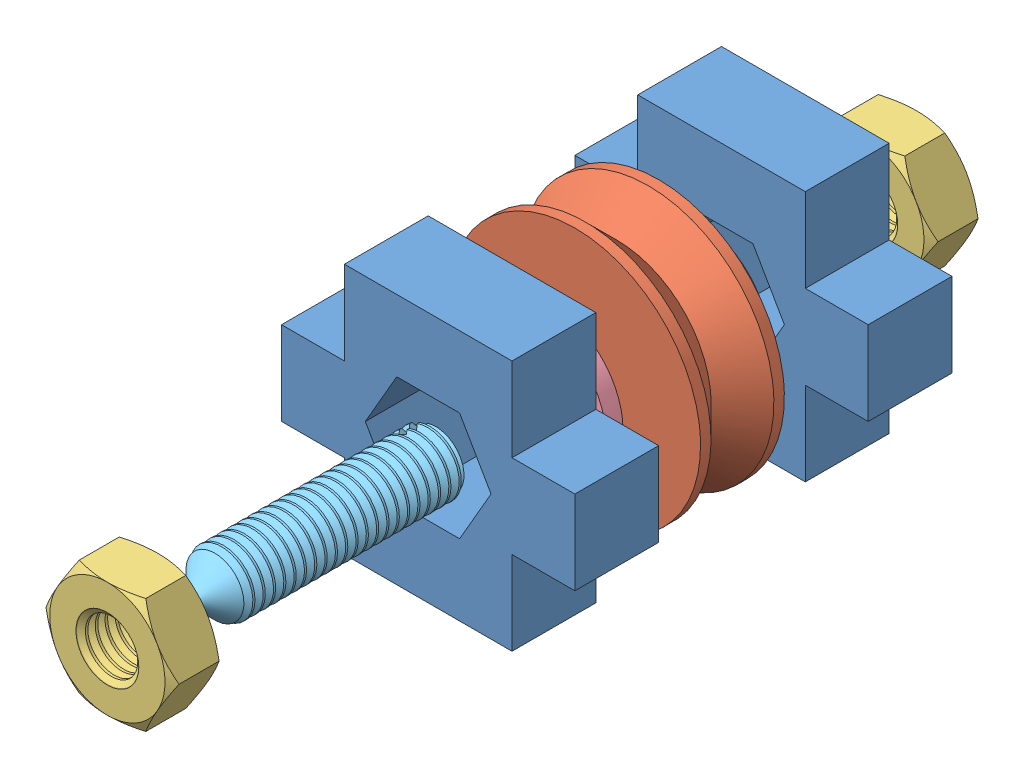
SolidWorks assembly pulleyInsidePalm, configuration Default. Lengths in mm.
Overall size (14 13.03 38.8).
8 component instances, 5 part files, 17 mates.
Components (placement in the parent):
- BasePulleyInsidePalm-1: BasePulleyInsidePalm [Default] at (-0.6961 4.81 7.3798) size (14 12 4)
- BasePulleyInsidePalm-2: BasePulleyInsidePalm [Default] at (-0.6961 4.81 21.3798) size (14 12 4)
- pulley-1: pulley [Default] at (3.3039 10.81 14.3798) x (0.995915 0.090298 0) z (0 0 1) size (12 12 4)
- hex nut style 1 gradeab_din-2: hex nut style 1 gradeab_din [Hexagon Nut ISO 4032 - M3 - D - S] at (3.3916 10.6581 40.7798) x (0.866025 -0.5 0) z (0 0 1) size (5.5 6.35 2.4)
- hex nut style 1 gradeab_din-3: hex nut style 1 gradeab_din [Hexagon Nut ISO 4032 - M3 - D - S] at (3.2162 10.6581 4.3798) x (0.866025 -0.5 0) z (0 0 1) size (5.5 6.35 2.4)
- plain washer 6902 type abc_din-1: plain washer 6902 type abc_din [DIN 6902-C3.2] at (3.3039 10.81 20.3798) x (0 0 -1) z (0.829839 0.558003 0) size (0.8 7 7)
- plain washer 6902 type abc_din-2: plain washer 6902 type abc_din [DIN 6902-C3.2] at (3.3039 10.81 12.5798) x (0 0 1) z (-1 0 0) size (0.8 7 7)
- slotted set screw cone point_din-1: slotted set screw cone point_din [ISO 7434 - M3 x 12-S] at (3.3916 10.6581 25.03) x (0 0 1) z (0.454401 -0.890797 0) size (12 3 3)
Mates (geometry in assembly coordinates):
- Coincident1: coincident aligned: plane of BasePulleyInsidePalm-1 through (-3.6961 12.81 11.3798) normal (-1 0 0); plane of BasePulleyInsidePalm-2 through (-3.6961 12.81 25.3798) normal (-1 0 0)
- Coincident2: coincident aligned: plane of BasePulleyInsidePalm-1 through (7.3039 16.81 11.3798) normal (0 1 0); plane of BasePulleyInsidePalm-2 through (7.3039 16.81 25.3798) normal (0 1 0)
- Distance1: distance = 10 mm anti-aligned: plane of BasePulleyInsidePalm-1 through (-0.6961 4.81 11.3798) normal (0 0 1); plane of BasePulleyInsidePalm-2 through (-0.6961 4.81 21.3798) normal (0 0 -1)
- Distance2: distance = 1.5 mm: line of BasePulleyInsidePalm-1 through (6.3039 10.81 11.3798) axis (0 0 -1); cylinder of pulley-1 through (3.3039 10.81 16.3798) axis (0 0 -1) radius 1.5
- Distance3: distance = 1.5 mm: cylinder of pulley-1 through (3.3039 10.81 16.3798) axis (0 0 -1) radius 1.5; line of BasePulleyInsidePalm-1 through (0.3039 10.81 11.3798) axis (0 0 -1)
- Distance4: distance = 3 mm anti-aligned: plane of pulley-1 through (3.3039 10.81 14.3798) normal (0 0 -1); plane of BasePulleyInsidePalm-1 through (-0.6961 4.81 11.3798) normal (0 0 1)
- Coincident7: coincident anti-aligned: plane of BasePulleyInsidePalm-2 through (1.8039 13.4081 25.3798) normal (0.866025 -0.5 0); plane of hex nut style 1 gradeab_din-2 through (1.8039 13.4081 38.3798) normal (-0.866025 0.5 0)
- Distance5: distance = 20 mm anti-aligned: plane of pulley-1 through (3.3039 10.81 18.3798) normal (0 0 1); plane of hex nut style 1 gradeab_din-2 through (4.9793 13.4081 38.3798) normal (0 0 -1)
- Coincident12: coincident anti-aligned: plane of BasePulleyInsidePalm-2 through (4.8039 13.4081 25.3798) normal (0 -1 0); plane of hex nut style 1 gradeab_din-2 through (4.9793 13.4081 38.3798) normal (0 1 0)
- Coincident13: coincident anti-aligned: plane of BasePulleyInsidePalm-1 through (6.3039 10.81 11.3798) normal (-0.866025 -0.5 0); plane of hex nut style 1 gradeab_din-3 through (6.3916 10.6581 1.9798) normal (0.866025 0.5 0)
- Coincident14: coincident anti-aligned: plane of BasePulleyInsidePalm-1 through (4.8039 13.4081 11.3798) normal (0 -1 0); plane of hex nut style 1 gradeab_din-3 through (4.8039 13.4081 1.9798) normal (0 1 0)
- Distance6: distance = 3 mm anti-aligned: plane of BasePulleyInsidePalm-1 through (-0.6961 4.81 7.3798) normal (0 0 -1); plane of hex nut style 1 gradeab_din-3 through (4.8039 13.4081 4.3798) normal (0 0 1)
- Concentric10: concentric anti-aligned: cylinder of pulley-1 through (3.3039 10.81 16.3798) axis (0 0 -1) radius 1.5; cylinder of plain washer 6902 type abc_din-1 through (3.3039 10.81 19.5798) axis (0 0 1) radius 1.6
- Distance8: distance = 1 mm anti-aligned: plane of plain washer 6902 type abc_din-1 through (3.3039 10.81 20.3798) normal (0 0 1); plane of BasePulleyInsidePalm-2 through (-0.6961 4.81 21.3798) normal (0 0 -1)
- Distance9: distance = 1 mm anti-aligned: plane of plain washer 6902 type abc_din-2 through (3.3039 10.81 13.3798) normal (0 0 1); plane of pulley-1 through (3.3039 10.81 14.3798) normal (0 0 -1)
- Concentric11: concentric aligned: cylinder of pulley-1 through (3.3039 10.81 16.3798) axis (0 0 -1) radius 1.5; cylinder of plain washer 6902 type abc_din-2 through (3.3039 10.81 13.3798) axis (0 0 -1) radius 1.6
- Concentric12: concentric anti-aligned: circle of hex nut style 1 gradeab_din-2; circle of slotted set screw cone point_din-1
